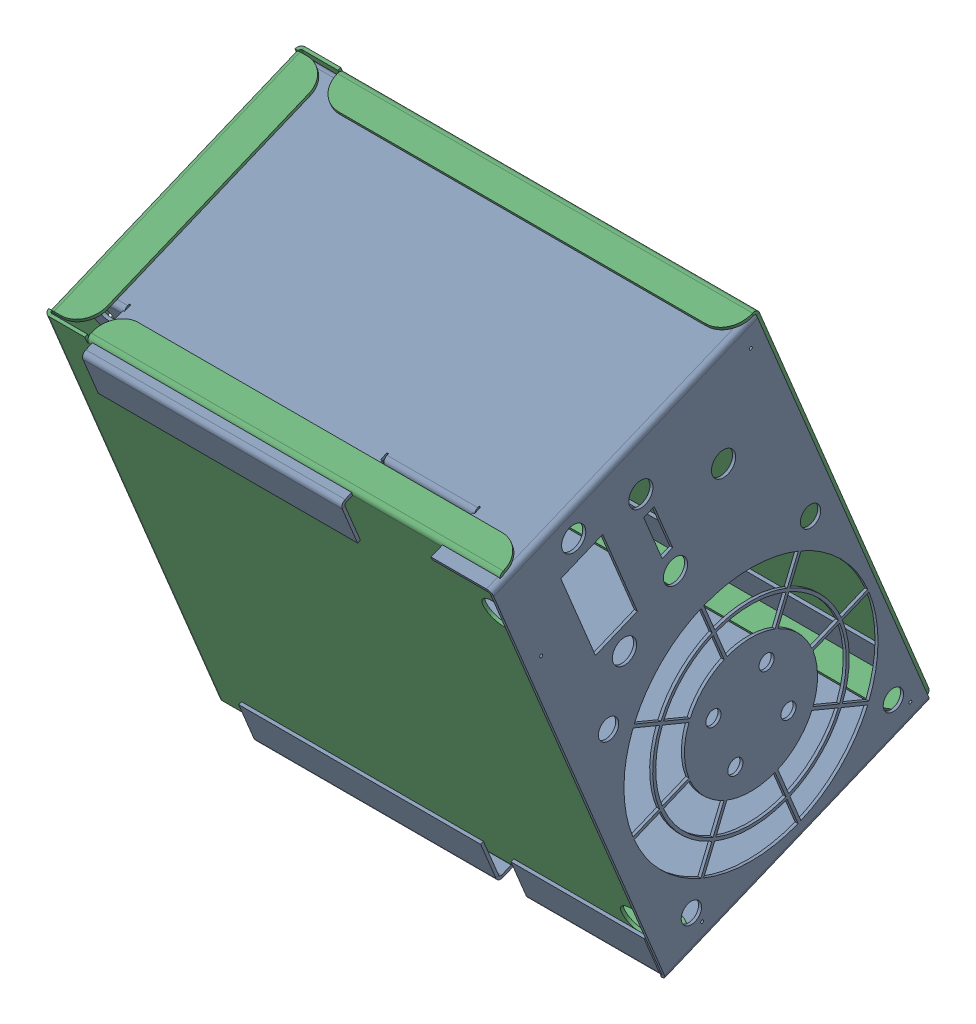
SolidWorks assembly lab_linear_power_supply_assem1, configuration Default. Lengths in mm.
Overall size (151.28 177.43 145.18).
2 component instances, 2 part files, 3 mates.
Components (placement in the parent):
- Part2-1: Part2 [Default] at (-61.4444 110.1296 84.6469) x (1 0 0) z (0 -0.381849 0.924225) size (150.77 151.53 94.48)
- Part1-1: Part1 [Default] at (84.5429 96.957 74.9304) x (-1 0 0) z (0 -0.924225 -0.381849) size (151.28 91.53 150)
Mates (geometry in assembly coordinates):
- Coincident1: coincident aligned: plane of Part2-1 through (89.321 -27.7967 27.6617) normal (1 0 0); plane of Part1-1 through (89.321 148.5461 -1.7084) normal (1 0 0)
- Coincident2: coincident anti-aligned: plane of Part2-1 through (388.5556 250.1781 142.5088) normal (0 0.924225 0.381849); plane of Part1-1 through (84.5429 251.6865 138.8579) normal (0 -0.924225 -0.381849)
- Coincident3: coincident anti-aligned: plane of Part2-1 through (239.321 146.9145 -2.3825) normal (0 0.381849 -0.924225); plane of Part1-1 through (-105.679 162.4095 4.0193) normal (0 -0.381849 0.924225)
